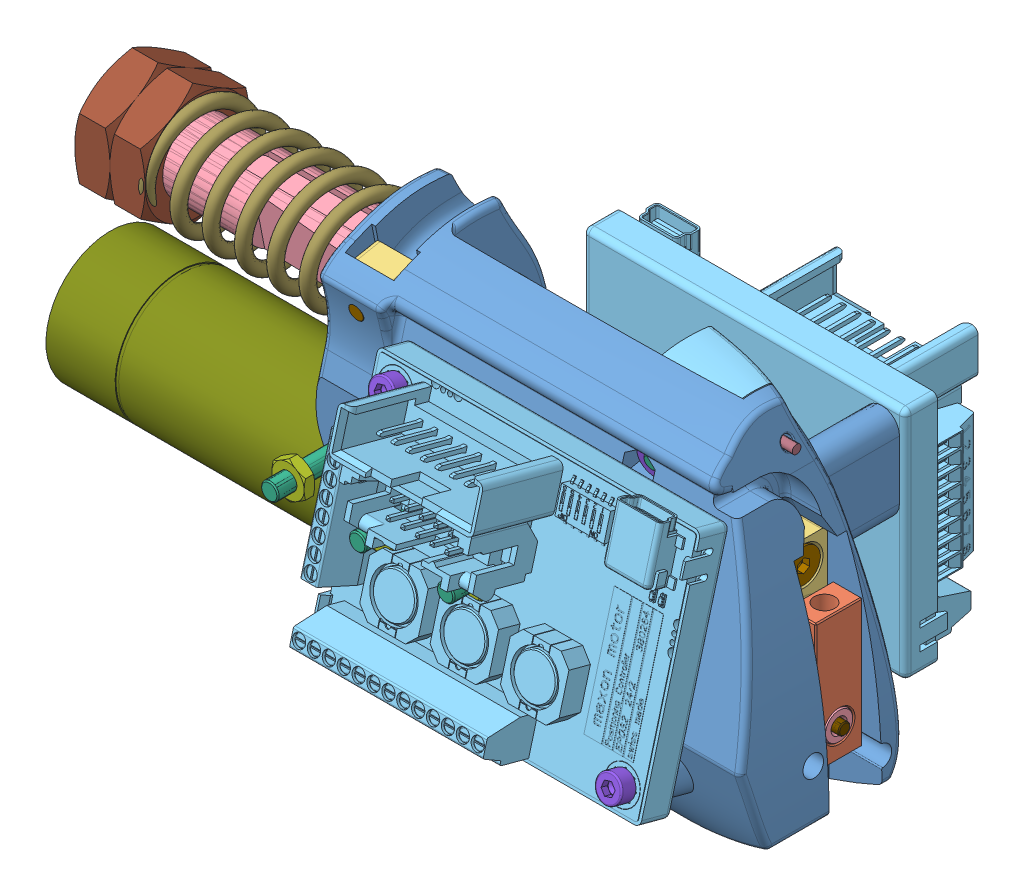
SolidWorks assembly a-antriebstrang-bein-links-v05, configuration Slave-BoardPosition 1. Lengths in mm.
Overall size (130.8 65.2 78.85).
43 component instances, 26 part files, 38 mates.
Components (placement in the parent):
- a-motorträger-beine-links-v01-1: a-motorträger-beine-links-v01 [01] x (-1 0 0) z (0 0 -1) size (130.38 65.2 41.74)
  - p-halterreferenz-links-v04-1: p-halterreferenz-links-v04 [01] at (-8 0 0) x (0 0 -1) z (1 0 0) size (41.74 65.2 84.36)
  - z-jfm-0608-06-v01-1: z-jfm-0608-06-v01 [01] at (-23.3 0 0) x (-1 0 0) z (0 0 -1) size (6 12 12)
  - z-induktiv-sensor-v01-1: z-induktiv-sensor-v01 [01] at (37 21.9082 -7.6275) x (-1 0 0) z (0 0.190809 0.981627) size (8 16 4.7)
  - z-induktiv-sensor-v01-2: z-induktiv-sensor-v01 [01] at (-25.5 8.63 4) x (0 0 -1) z (-1 0 0) size (8 16 4.7)
  - p-federstössel-v01-1: p-federstössel-v01 [01] at (77.9 27.8 1.72) x (-1 0 0) z (0 -0.190809 -0.981627) size (77 12 12)
  - p-halterdeckel-links-v02-1: p-halterdeckel-links-v02 [01] at (-8 0 0) x (0 0 -1) z (1 0 0) size (28.27 33.45 14.71)
  - z-passschraube-misumi-4-v01-1: z-passschraube-misumi-4-v01 [01] at (-13.1 35.2829 8.5672) x (0 -0.190809 -0.981627) z (-0.839411 0.533511 -0.103704) size (18 6.5 6.5)
  - z-passschraube-misumi-4-v01-2: z-passschraube-misumi-4-v01 [01] at (-13.1 16.1412 12.288) x (0 -0.190809 -0.981627) z (-0.58333 -0.797312 0.154982) size (18 6.5 6.5)
  - Lock washer DIN 6799 - 7-8: Lock washer DIN 6799 - 7 [Lock washer DIN 6799 - 7] at (24 27.8 1.72) x (0 0 1) z (-1 0 0) size (14.3 11.94 0.9)
  - Hexagon Nut ISO 4032 - M2.5 - W - N-13: Hexagon Nut ISO 4032 - M2.5 - W - N [Hexagon Nut ISO 4032 - M2.5 - W - N] at (-13.1 31.8991 -8.8409) x (0.5 0.850114 -0.165245) z (0 -0.190809 -0.981627) size (5 5.77 2)
  - Hexagon Nut ISO 4032 - M2.5 - W - N-14: Hexagon Nut ISO 4032 - M2.5 - W - N [Hexagon Nut ISO 4032 - M2.5 - W - N] at (-13.1 12.7574 -5.1202) x (0.5 0.850114 -0.165245) z (0 -0.190809 -0.981627) size (5 5.77 2)
  - DIN 7991 - M3 x 8 --- 4.8C-13: DIN 7991 - M3 x 8 --- 4.8C [DIN 7991 - M3 x 8 --- 4.8C] at (-30.15 20.63 0) size (8 5.7 5.7)
  - DIN 7991 - M3 x 8 --- 4.8C-14: DIN 7991 - M3 x 8 --- 4.8C [DIN 7991 - M3 x 8 --- 4.8C] at (33 34.5749 -5.3527) x (0 -0.190809 -0.981627) z (-0.981627 -0.187303 0.036408) size (8 5.7 5.7)
  - p-oese-v01-1: p-oese-v01 [01] at (-25.5 37.4 0) size (3.5 4 4)
  - Hexagon Thin Nut ISO 4035 - M12 - N-13: Hexagon Thin Nut ISO 4035 - M12 - N [Hexagon Thin Nut ISO 4035 - M12 - N] at (74.9 27.8 1.72) x (0 -0.006521 -0.999979) z (-1 0 0) size (18 20.78 6)
  - Hexagon Thin Nut ISO 4035 - M12 - N-14: Hexagon Thin Nut ISO 4035 - M12 - N [Hexagon Thin Nut ISO 4035 - M12 - N] at (80.9 27.8 1.72) x (0 0 1) z (-1 0 0) size (18 20.78 6)
  - z-feder-febrotec-v01-1: z-feder-febrotec-v01 [01] at (40 27.5466 1.7693) x (1 0 0) z (0 -0.190809 -0.981627) size (40.25 20.98 20.5)
  - p-seil-v02-1: p-seil-v02 [01] at (-16.85 -0.1381 7.1506) x (-1 0 0) z (0 -0.190809 -0.981627) size (48.5 39 1.5)
  - p-umlenkpulley-v06-1: p-umlenkpulley-v06 [01] at (-13.1 33.728 0.5677) x (0 -0.190809 -0.981627) z (-0.981627 -0.187303 0.036408) size (3.6 7.15 7.15)
  - p-umlenkpulley-v06-4: p-umlenkpulley-v06 [01] at (-13.1 14.5863 4.2885) x (0 -0.190809 -0.981627) z (-0.997632 -0.067518 0.013124) size (3.6 7.15 7.15)
  - p-umlenkpulley-v06-3: p-umlenkpulley-v06 [01] at (14.9 27.8 1.72) x (0 -0.190809 -0.981627) z (-0.981627 -0.187303 0.036408) size (3.6 7.15 7.15)
  - Parallel Pin ISO 2338 - 4 h6 x 10 - St-8: Parallel Pin ISO 2338 - 4 h6 x 10 - St [Parallel Pin ISO 2338 - 4 h6 x 10 - St] at (14.9 28.754 6.6281) x (0 -0.190809 -0.981627) z (-0.981627 -0.187303 0.036408) size (10 4 4)
- a-Maxon-EC22-386675-v01-2: a-Maxon-EC22-386675-v01 [01] at (-25.4 0 0) x (-1 0 0) z (0 0.984807 0.17365) size (103.18 22 22)
  - z-Motor-Maxon-EC22-386673-v01-1: z-Motor-Maxon-EC22-386673-v01 [01] at origin size (73.23 22 22)
  - z-Getriebe-Maxon-GP22C_1-STUFIG-143972-v01-1: z-Getriebe-Maxon-GP22C_1-STUFIG-143972-v01 [01] at (-25.4 0 0) size (40.25 22 22)
- p-motorpulley-v04-2: p-motorpulley-v04 [01] at (3.15 0 0) x (1 0 0) z (0 -0.17365 0.984807) size (35.05 9 9)
- DIN 913 - M2 x 3-C-7: DIN 913 - M2 x 3-C [DIN 913 - M2 x 3-C] at (10.15 -0.7814 4.4316) x (0 0.17365 -0.984807) z (1 0 0) size (3 2 2)
- p-absolutmess-plättchen-v04-2: p-absolutmess-plättchen-v04 [01] at (36.2 0 0) x (0 0 1) z (-1 0 0) size (8 22 5)
- ISO 2010 - M2.5 x 10 --- 10C-20: ISO 2010 - M2.5 x 10 --- 10C [ISO 2010 - M2.5 x 10 --- 10C] at (9 6.5778 -2.3941) x (-1 0 0) z (0 -0.814507 -0.580154) size (10.59 4.7 4.66)
- ISO 2010 - M2.5 x 10 --- 10C-21: ISO 2010 - M2.5 x 10 --- 10C [ISO 2010 - M2.5 x 10 --- 10C] at (9 -1.2155 6.8937) x (-1 0 0) z (0 -0.924225 -0.381849) size (10.59 4.7 4.66)
- ISO 2010 - M2.5 x 10 --- 10C-22: ISO 2010 - M2.5 x 10 --- 10C [ISO 2010 - M2.5 x 10 --- 10C] at (9 -5.3623 -4.4995) x (-1 0 0) z (0 -0.849021 0.528359) size (10.59 4.7 4.66)
- p-gewindeeinsatz-v01-1: p-gewindeeinsatz-v01 [01] at (30.2 0 0) x (1 0 0) z (0 -0.998486 -0.054998) size (6 5 5)
- z-380264_epos2_24_2-v01-3: z-380264_epos2_24_2-v01 [01] at (2 14 -22) x (1 0 0) z (0 1 0) size (55.21 20.01 40.39)
- z-380264_epos2_24_2-v01-4: z-380264_epos2_24_2-v01 [01] at (2 14.1149 20.6087) x (-1 0 0) z (0 0.965926 -0.258819) size (55.21 20.01 40.39)
- z-zyl-schr-schaft-M3x40-v01-4: z-zyl-schr-schaft-M3x40-v01 [01] at (-32 15 -14) x (0 0 1) z (-1 0 0) size (43 5.5 5.5)
- Hexagon Thin Nut ISO 4035 - M3 - C-9: Hexagon Thin Nut ISO 4035 - M3 - C [Hexagon Thin Nut ISO 4035 - M3 - C] at (-32 15 25.8) size (5.5 6.35 1.8)
- Hexagon Thin Nut ISO 4035 - M3 - C-15: Hexagon Thin Nut ISO 4035 - M3 - C [Hexagon Thin Nut ISO 4035 - M3 - C] at (-17 15 25.8) size (5.5 6.35 1.8)
- Hexagon Thin Nut ISO 4035 - M3 - C-16: Hexagon Thin Nut ISO 4035 - M3 - C [Hexagon Thin Nut ISO 4035 - M3 - C] at (-2 15 25.8) size (5.5 6.35 1.8)
- z-zyl-schr-schaft-M3x40-v01-5: z-zyl-schr-schaft-M3x40-v01 [01] at (-17 15 -14) x (0 0 1) z (-1 0 0) size (43 5.5 5.5)
- z-zyl-schr-schaft-M3x40-v01-6: z-zyl-schr-schaft-M3x40-v01 [01] at (-2 15 -14) x (0 0 1) z (-1 0 0) size (43 5.5 5.5)
- n-zyl-schr-i6kt-M2.5x8 (BN11)-2: n-zyl-schr-i6kt-M2.5x8 (BN11) [n-zyl-schr-i6kt-M2.5x8 (BN11)] at (-21.5 30.6309 20.4279) x (0 -0.258819 -0.965926) z (0.965926 -0.25 0.066987) size (10.5 4.5 4.5)
- n-zyl-schr-i6kt-M2.5x8 (BN11)-3: n-zyl-schr-i6kt-M2.5x8 (BN11) [n-zyl-schr-i6kt-M2.5x8 (BN11)] at (25.5 -0.2788 28.7101) x (0 -0.258819 -0.965926) z (0.965926 -0.25 0.066987) size (10.5 4.5 4.5)
Mates (geometry in assembly coordinates):
- Konzentrisch1: concentric aligned: cylinder of a-motorträger-beine-links-v01-1/p-halterreferenz-links-v04-1 through (0 0 0) axis (-1 0 0) radius 11.5; cylinder of a-Maxon-EC22-386675-v01-2/z-Getriebe-Maxon-GP22C_1-STUFIG-143972-v01-1 through (0 0 0) axis (-1 0 0) radius 11
- Deckungsgleich1: coincident anti-aligned: plane of a-motorträger-beine-links-v01-1/p-halterreferenz-links-v04-1 through (0 0 0) normal (-1 0 0); plane of a-Maxon-EC22-386675-v01-2/z-Getriebe-Maxon-GP22C_1-STUFIG-143972-v01-1 through (0 0 0) normal (1 0 0)
- Deckungsgleich2: coincident anti-aligned: plane of a-motorträger-beine-links-v01-1 through (0 0 0) normal (0 0 -1); plane of assembly through (0 0 0) normal (0 0 1)
- Deckungsgleich3: coincident aligned: plane of a-motorträger-beine-links-v01-1; plane of assembly through (0 0 0) normal (0 1 0)
- Deckungsgleich4: coincident anti-aligned: plane of a-motorträger-beine-links-v01-1 through (0 0 0) normal (-1 0 0); plane of assembly through (0 0 0) normal (1 0 0)
- Konzentrisch2: concentric aligned: cylinder of a-Maxon-EC22-386675-v01-2/z-Getriebe-Maxon-GP22C_1-STUFIG-143972-v01-1 through (14.85 0 0) axis (-1 0 0) radius 2; cylinder of p-motorpulley-v04-2 through (3.15 0 0) axis (-1 0 0) radius 2
- Deckungsgleich5: coincident anti-aligned: plane of a-Maxon-EC22-386675-v01-2/z-Getriebe-Maxon-GP22C_1-STUFIG-143972-v01-1 through (3.15 0 0) normal (1 0 0); plane of p-motorpulley-v04-2 through (3.15 4.4316 0.7814) normal (-1 0 0)
- Konzentrisch3: concentric anti-aligned: cylinder of p-motorpulley-v04-2 through (10.15 0 0) axis (0 0.17365 -0.984807) radius 0.8; cylinder of DIN 913 - M2 x 3-C-7 through (10.15 -2.9868 16.9387) axis (0 -0.17365 0.984807) radius 1
- Parallel2: parallel aligned: plane of a-Maxon-EC22-386675-v01-2/z-Getriebe-Maxon-GP22C_1-STUFIG-143972-v01-1 through (10.2 -0.2605 1.4772) normal (0 -0.17365 0.984807); plane of p-motorpulley-v04-2 through (3.15 0 0) normal (0 -0.17365 0.984807)
- Deckungsgleich7: coincident anti-aligned: plane of a-Maxon-EC22-386675-v01-2/z-Getriebe-Maxon-GP22C_1-STUFIG-143972-v01-1 through (10.2 -0.2605 1.4772) normal (0 -0.17365 0.984807); plane of DIN 913 - M2 x 3-C-7 through (10.15 0.2319 1.564) normal (0 0.17365 -0.984807)
- Parallel3: parallel anti-aligned: plane of a-motorträger-beine-links-v01-1/p-halterreferenz-links-v04-1 through (30 0 -4.5) normal (0 0 1); plane of p-absolutmess-plättchen-v04-2 through (31.2 -5 -4) normal (0 0 -1)
- Abstand1: distance = 1 mm anti-aligned: plane of a-motorträger-beine-links-v01-1/z-induktiv-sensor-v01-2 through (30.2 8.63 -4) normal (1 0 0); plane of p-absolutmess-plättchen-v04-2 through (31.2 0 0) normal (-1 0 0)
- Konzentrisch5: concentric anti-aligned: cylinder of p-motorpulley-v04-2 through (3.15 0 0) axis (-1 0 0) radius 1; cylinder of p-absolutmess-plättchen-v04-2 through (31.2 0 0) axis (1 0 0) radius 2.5
- Konzentrisch6: concentric aligned: cylinder of a-motorträger-beine-links-v01-1/p-halterreferenz-links-v04-1 through (-42.3814 -5.3623 -4.4995) axis (1 0 0) radius 1.5; cylinder of a-Maxon-EC22-386675-v01-2/z-Getriebe-Maxon-GP22C_1-STUFIG-143972-v01-1 through (-4 -5.3623 -4.4995) axis (1 0 0) radius 1.025
- Konzentrisch29: concentric aligned: cylinder of ISO 2010 - M2.5 x 10 --- 10C-21 through (24.875 -1.2155 6.8937) axis (1 0 0) radius 1.25; cylinder of a-motorträger-beine-links-v01-1/p-halterreferenz-links-v04-1 through (-42.3814 -1.2155 6.8937) axis (1 0 0) radius 1.5
- Deckungsgleich16: coincident aligned: cone of a-motorträger-beine-links-v01-1/p-halterreferenz-links-v04-1 through (8 -1.2155 6.8937) axis (-1 0 0); cone of ISO 2010 - M2.5 x 10 --- 10C-21 through (8 -1.2155 6.8937) axis (-1 0 0)
- Konzentrisch31: concentric aligned: cylinder of a-motorträger-beine-links-v01-1/p-halterreferenz-links-v04-1 through (-42.3814 6.5778 -2.3941) axis (1 0 0) radius 1.5; cylinder of ISO 2010 - M2.5 x 10 --- 10C-20 through (24.875 6.5778 -2.3941) axis (1 0 0) radius 1.25
- Deckungsgleich17: coincident aligned: cone of a-motorträger-beine-links-v01-1/p-halterreferenz-links-v04-1 through (8 6.5778 -2.3941) axis (-1 0 0); cone of ISO 2010 - M2.5 x 10 --- 10C-20 through (8 6.5778 -2.3941) axis (-1 0 0)
- Konzentrisch33: concentric aligned: cylinder of a-motorträger-beine-links-v01-1/p-halterreferenz-links-v04-1 through (-42.3814 -5.3623 -4.4995) axis (1 0 0) radius 1.5; cylinder of ISO 2010 - M2.5 x 10 --- 10C-22 through (24.875 -5.3623 -4.4995) axis (1 0 0) radius 1.25
- Deckungsgleich18: coincident aligned: cone of a-motorträger-beine-links-v01-1/p-halterreferenz-links-v04-1 through (8 -5.3623 -4.4995) axis (-1 0 0); cone of ISO 2010 - M2.5 x 10 --- 10C-22 through (8 -5.3623 -4.4995) axis (-1 0 0)
- Konzentrisch318: concentric anti-aligned: cylinder of p-absolutmess-plättchen-v04-2 through (31.2 0 0) axis (1 0 0) radius 2.5; cylinder of p-gewindeeinsatz-v01-1 through (30.2 0 0) axis (-1 0 0) radius 2.5
- Deckungsgleich150: coincident aligned: plane of p-absolutmess-plättchen-v04-2 through (36.2 0 0) normal (1 0 0); plane of p-gewindeeinsatz-v01-1 through (36.2 -0.0275 0.4992) normal (1 0 0)
- Konzentrisch323: concentric anti-aligned: cylinder of z-zyl-schr-schaft-M3x40-v01-4 through (-32 15 -14) axis (0 0 -1) radius 1.5; cylinder of Hexagon Thin Nut ISO 4035 - M3 - C-9 through (-32 15 24) axis (0 0 1) radius 1.25
- Abstand2: distance = 35 mm anti-aligned: plane of z-zyl-schr-schaft-M3x40-v01-4 through (-32 17.75 -11) normal (0 0 1); plane of Hexagon Thin Nut ISO 4035 - M3 - C-9 through (-37.5 15 24) normal (0 0 -1)
- Konzentrisch324: concentric anti-aligned: cylinder of a-motorträger-beine-links-v01-1/p-halterreferenz-links-v04-1 through (-32 15 22.5327) axis (0 0 1) radius 2; cylinder of z-zyl-schr-schaft-M3x40-v01-4 through (-32 15 -14) axis (0 0 -1) radius 1.5
- Deckungsgleich154: coincident anti-aligned: plane of a-motorträger-beine-links-v01-1/p-halterreferenz-links-v04-1 through (-30 15 -11) normal (0 0 -1); plane of z-zyl-schr-schaft-M3x40-v01-4 through (-32 17.75 -11) normal (0 0 1)
- Konzentrisch325: concentric aligned: cylinder of a-motorträger-beine-links-v01-1/p-halterreferenz-links-v04-1 through (-32 15 22.5327) axis (0 0 1) radius 2; cylinder of z-zyl-schr-schaft-M3x40-v01-4 through (-32 15 11) axis (0 0 1) radius 1.5
- Deckungsgleich155: coincident anti-aligned: plane of a-motorträger-beine-links-v01-1/p-halterreferenz-links-v04-1 through (-28.75 15 8) normal (0 0 1); plane of z-zyl-schr-schaft-M3x40-v01-4 through (-30.9466 12.4597 8) normal (0 0 -1)
- Konzentrisch326: concentric anti-aligned: cylinder of a-motorträger-beine-links-v01-1/p-halterreferenz-links-v04-1 through (-21.5 -2 22.2036) axis (0 0 -1) radius 0.9; circle of z-380264_epos2_24_2-v01-3
- Konzentrisch327: concentric aligned: cylinder of a-motorträger-beine-links-v01-1/p-halterreferenz-links-v04-1 through (25.5 30 22.2036) axis (0 0 -1) radius 0.9; cylinder of z-380264_epos2_24_2-v01-3 through (25.5 30 -23.6) axis (0 0 -1) radius 1.35
- Deckungsgleich156: coincident anti-aligned: plane of a-motorträger-beine-links-v01-1/p-halterreferenz-links-v04-1 through (25.5 30 -18) normal (0 0 -1); plane of z-380264_epos2_24_2-v01-3 through (2 14 -18) normal (0 0 1)
- Deckungsgleich157: coincident anti-aligned: plane of a-motorträger-beine-links-v01-1/p-halterreferenz-links-v04-1 through (8 5.0624 18.8932) normal (0 0.258819 0.965926); plane of z-380264_epos2_24_2-v01-4 through (2 13.0796 16.745) normal (0 -0.258819 -0.965926)
- Konzentrisch328: concentric aligned: cylinder of a-motorträger-beine-links-v01-1/p-halterreferenz-links-v04-1 through (-21.5 26.2089 3.9248) axis (0 0.258819 0.965926) radius 0.9; cylinder of z-380264_epos2_24_2-v01-4 through (-21.5 29.9838 18.0131) axis (0 0.258819 0.965926) radius 1.35
- Konzentrisch329: concentric aligned: cylinder of a-motorträger-beine-links-v01-1/p-halterreferenz-links-v04-1 through (25.5 -13.7717 -21.6463) axis (0 0.258819 0.965926) radius 0.9; cylinder of z-380264_epos2_24_2-v01-4 through (25.5 -0.9258 26.2953) axis (0 0.258819 0.965926) radius 1.35
- Konzentrisch330: concentric aligned: cylinder of z-380264_epos2_24_2-v01-4 through (25.5 -0.9258 26.2953) axis (0 0.258819 0.965926) radius 1.35; cylinder of n-zyl-schr-i6kt-M2.5x8 (BN11)-3 through (25.5 7.9387 59.3783) axis (0 0.258819 0.965926) radius 1.25
- Deckungsgleich158: coincident anti-aligned: plane of z-380264_epos2_24_2-v01-4 through (25.5 -0.9258 26.2953) normal (0 0.258819 0.965926); plane of n-zyl-schr-i6kt-M2.5x8 (BN11)-3 through (26.0823 1.1735 25.7328) normal (0 -0.258819 -0.965926)
- Konzentrisch331: concentric aligned: cylinder of z-380264_epos2_24_2-v01-4 through (-21.5 29.9838 18.0131) axis (0 0.258819 0.965926) radius 1.35; cylinder of n-zyl-schr-i6kt-M2.5x8 (BN11)-2 through (-21.5 38.8484 51.0961) axis (0 0.258819 0.965926) radius 1.25
- Deckungsgleich159: coincident anti-aligned: plane of z-380264_epos2_24_2-v01-4 through (-21.5 29.9838 18.0131) normal (0 0.258819 0.965926); plane of n-zyl-schr-i6kt-M2.5x8 (BN11)-2 through (-20.9177 32.0831 17.4506) normal (0 -0.258819 -0.965926)
